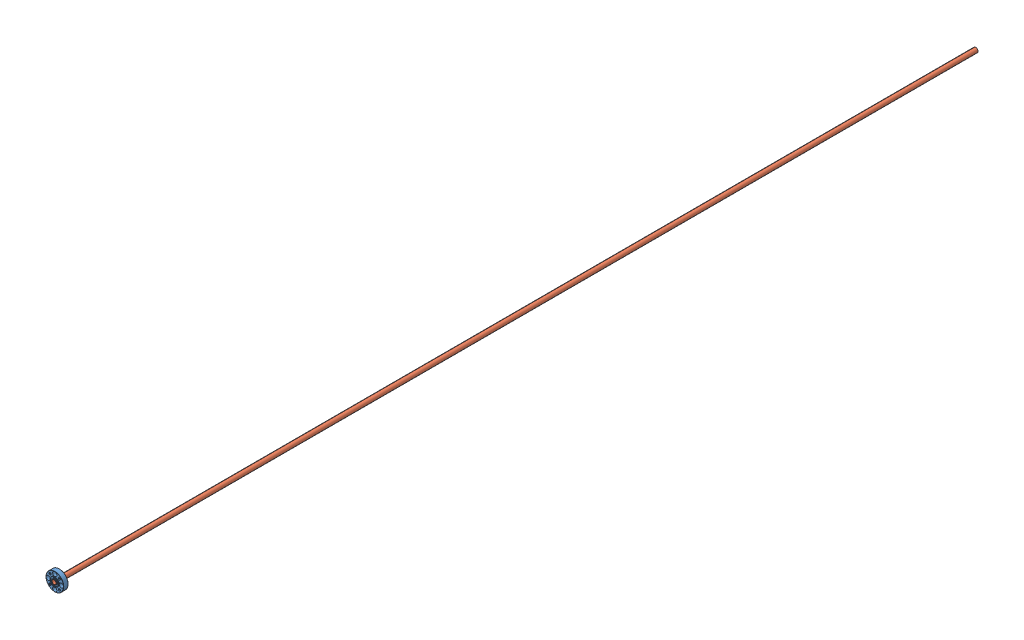
SolidWorks assembly Assem5, configuration Default. Lengths in mm.
Overall size (19.2 19.2 1000).
2 component instances, 2 part files, 2 mates.
Components (placement in the parent):
- UG387_1_O-ring-blind-1: UG387_1_O-ring-blind [Default] at origin size (19.2 19.2 5.99)
- Waveguide-1: Waveguide [Default] at (0 0 -994.24) size (5.06 5.06 1000)
Mates (geometry in assembly coordinates):
- Concentric1: concentric: circle of UG387_1_O-ring-blind-1; circle of Waveguide-1
- Coincident1: coincident aligned: plane of UG387_1_O-ring-blind-1 through (0 0 5.76) normal (0 0 1); plane of Waveguide-1 through (0 0 5.76) normal (0 0 1)
